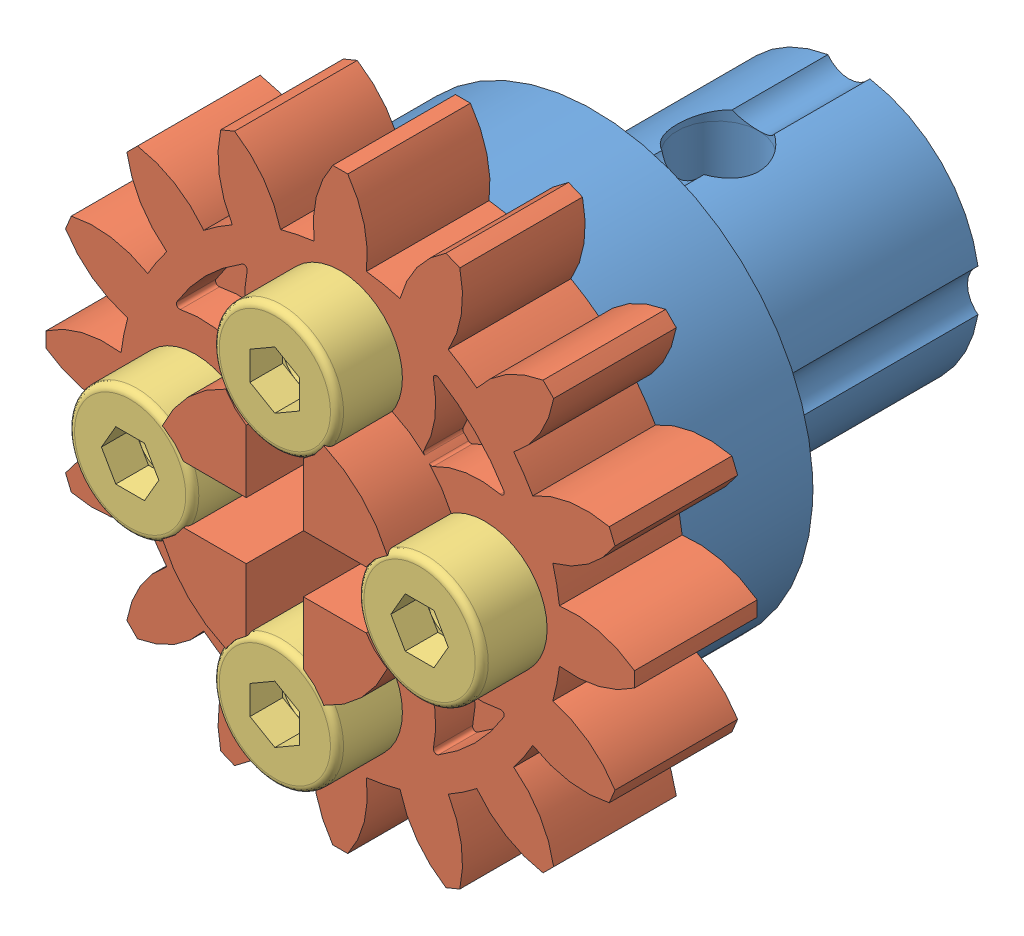
SolidWorks assembly Adapter-Motor-Zahnrad-16Z, configuration Standard. Lengths in mm.
Overall size (18 18 17.55).
6 component instances, 3 part files, 9 mates.
Components (placement in the parent):
- Adapter-Motor-Zahnrad-16Z-1: Adapter-Motor-Zahnrad-16Z [Standard] at origin size (13.4 13.4 11.8)
- Lego Zahnrad 16Z-1: Lego Zahnrad 16Z [Standard] at (0 0 5.875) size (18 18 7.75)
- DIN 912 M2 x 6 --- 6N-1: DIN 912 M2 x 6 --- 6N [DIN 912 M2 x 6 --- 6N] at (0 4.425 9.75) x (0 0 -1) z (1 0 0) size (8 3.8 3.8)
- DIN 912 M2 x 6 --- 6N-2: DIN 912 M2 x 6 --- 6N [DIN 912 M2 x 6 --- 6N] at (4.425 0 9.75) x (0 0 -1) z (0 -1 0) size (8 3.8 3.8)
- DIN 912 M2 x 6 --- 6N-3: DIN 912 M2 x 6 --- 6N [DIN 912 M2 x 6 --- 6N] at (0 -4.425 9.75) x (0 0 -1) z (-1 0 0) size (8 3.8 3.8)
- DIN 912 M2 x 6 --- 6N-4: DIN 912 M2 x 6 --- 6N [DIN 912 M2 x 6 --- 6N] at (-4.425 0 9.75) x (0 0 -1) z (0 1 0) size (8 3.8 3.8)
Mates (geometry in assembly coordinates):
- Deckungsgleich1: coincident aligned: plane of Adapter-Motor-Zahnrad-16Z-1 through (0 0 0) normal (0 0 1); plane of assembly through (0 0 0) normal (0 0 1)
- Deckungsgleich2: coincident aligned: plane of Adapter-Motor-Zahnrad-16Z-1 through (0 0 0) normal (0 1 0); plane of assembly through (0 0 0) normal (0 1 0)
- Deckungsgleich3: coincident aligned: plane of Adapter-Motor-Zahnrad-16Z-1 through (0 0 0) normal (1 0 0); plane of assembly through (0 0 0) normal (1 0 0)
- Konzentrisch1: concentric aligned: cylinder of Adapter-Motor-Zahnrad-16Z-1 through (0 0 4) axis (0 0 -1) radius 3.75; cylinder of Lego Zahnrad 16Z-1 through (0 0 9.75) axis (0 0 -1) radius 3.75
- Deckungsgleich5: coincident anti-aligned: plane of Adapter-Motor-Zahnrad-16Z-1 through (0 0 4) normal (0 0 1); plane of Lego Zahnrad 16Z-1 through (-15 -9 4) normal (0 0 -1)
- Parallel1: parallel aligned: plane of Adapter-Motor-Zahnrad-16Z-1 through (0 0 0) normal (1 0 0); plane of Lego Zahnrad 16Z-1 through (-0.875 0 2) normal (1 0 0)
- Konzentrisch2: concentric aligned: cylinder of Adapter-Motor-Zahnrad-16Z-1 through (0 4.425 4) axis (0 0 1) radius 0.8; cylinder of DIN 912 M2 x 6 --- 6N-1 through (0 4.425 41.5) axis (0 0 1) radius 1
- Deckungsgleich7: coincident anti-aligned: plane of Lego Zahnrad 16Z-1 through (-15 -9 7.75) normal (0 0 1); plane of DIN 912 M2 x 6 --- 6N-1 through (0 6.325 7.75) normal (0 0 -1)
- Deckungsgleich8: coincident aligned: plane of Adapter-Motor-Zahnrad-16Z-1 through (0 0 0) normal (1 0 0); plane of DIN 912 M2 x 6 --- 6N-1 through (0 4.425 9.75) normal (1 0 0)
